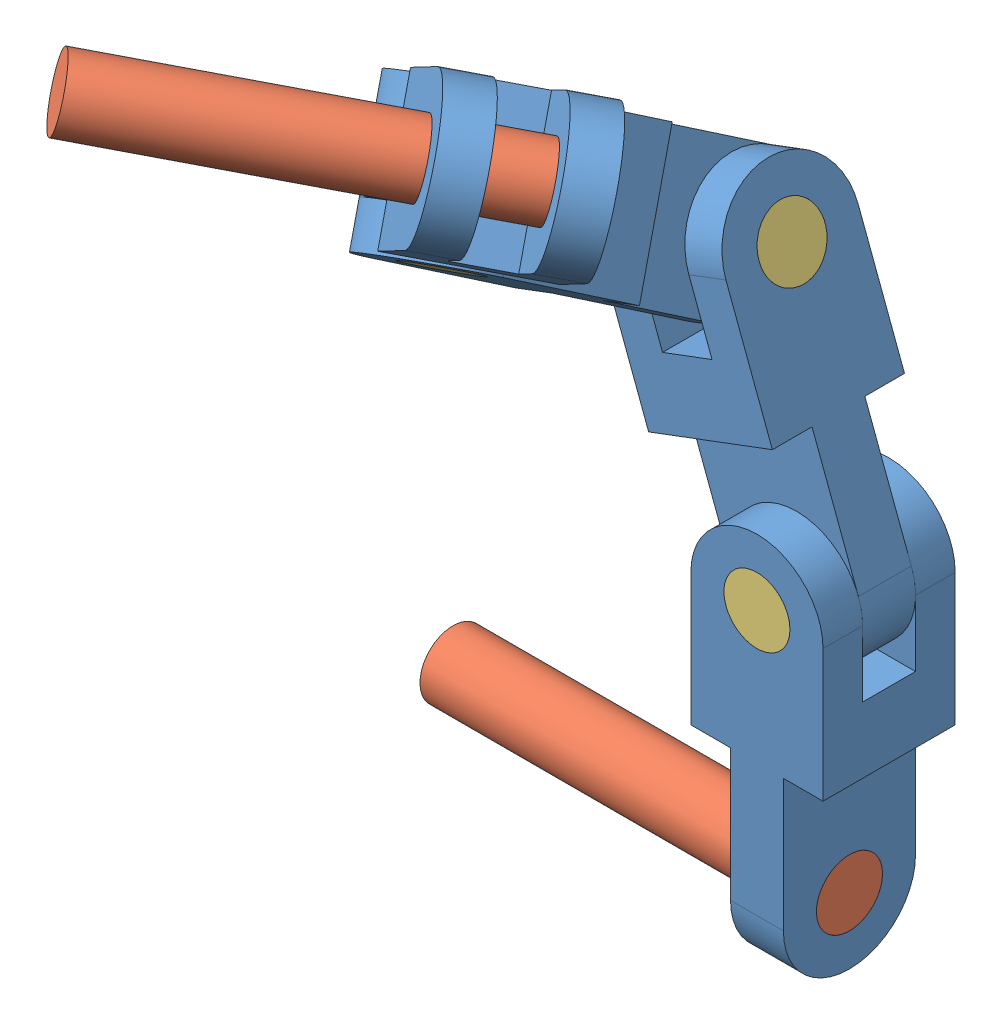
SolidWorks assembly Assem1 - Screens, configuration Default. Lengths in mm.
Overall size (388.38 745.02 528.55).
9 component instances, 3 part files, 19 mates.
Components (placement in the parent):
- chain_link-1: chain_link [Default] at (62.1432 144.0475 265.0733) size (100 300 100)
- long_pin-1: long_pin [Default] at (-217.8568 44.0475 265.0733) x (0 -0.416693 0.909047) z (0 -0.909047 -0.416693) size (50 300 50)
- short_pin-1: short_pin [Default] at (62.1432 244.0475 215.0733) x (1 0 0) z (0 1 0) size (50 100 50)
- chain_link-2: chain_link [Default] at (27.0048 337.6706 265.0733) x (0 0 1) z (-0.936232 -0.351384 0) size (100 300 100)
- chain_link-4: chain_link [Default] at (-27.2234 482.1572 349.0285) x (0.936232 0.351384 0) z (0.295005 -0.786016 0.543278) size (100 300 100)
- short_pin-3: short_pin [Default] at (-54.9451 413.7246 265.0733) x (-0.351384 0.936232 0) z (0 0 1) size (50 100 50)
- chain_link-5: chain_link [Default] at (20.9473 590.4881 479.6046) x (-0.295005 0.786016 -0.543278) z (0.678655 -0.227879 -0.698211) size (100 300 100)
- short_pin-4: short_pin [Default] at (-31.5631 493.7199 460.1477) x (0.703647 0.563374 0.433003) z (0.646416 -0.254538 -0.719275) size (50 100 50)
- long_pin-2: long_pin [Default] at (-81.4557 704.9252 700.7782) x (0.564085 0.77053 0.296803) z (0.470357 -0.595277 0.651467) size (50 300 50)
Mates (geometry in assembly coordinates):
- Concentric1: concentric anti-aligned: cylinder of chain_link-1 through (12.1432 44.0475 265.0733) axis (1 0 0) radius 25; axis of long_pin-1 through (82.1432 44.0475 265.0733) axis (-1 0 0)
- Coincident1: coincident anti-aligned: circle of chain_link-1; circle of long_pin-1
- Concentric2: concentric anti-aligned: cylinder of short_pin-1 through (62.1432 244.0475 315.0733) axis (0 0 -1) radius 25; cylinder of chain_link-2 through (62.1432 244.0475 215.0733) axis (0 0 1) radius 25
- Concentric3: concentric anti-aligned: cylinder of chain_link-1 through (62.1432 244.0475 215.0733) axis (0 0 1) radius 25; cylinder of short_pin-1 through (62.1432 244.0475 315.0733) axis (0 0 -1) radius 25
- Coincident2: coincident aligned: plane of chain_link-1 through (62.1432 244.0475 215.0733) normal (0 0 -1); circle of short_pin-1
- Coincident3: coincident anti-aligned: plane of chain_link-1 through (12.1432 294.0475 285.0733) normal (0 0 -1); plane of chain_link-2 through (62.1432 244.0475 285.0733) normal (0 0 1)
- Concentric8: concentric anti-aligned: line of chain_link-4 through (-26.8582 424.2661 265.0733) axis (0.936232 0.351384 0); cylinder of short_pin-3 through (38.678 448.863 265.0733) axis (-0.936232 -0.351384 0) radius 25
- Concentric9: concentric aligned: cylinder of chain_link-2 through (38.678 448.863 265.0733) axis (-0.936232 -0.351384 0) radius 25; cylinder of short_pin-3 through (38.678 448.863 265.0733) axis (-0.936232 -0.351384 0) radius 25
- Concentric10: concentric aligned: cylinder of chain_link-2 through (38.678 448.863 265.0733) axis (-0.936232 -0.351384 0) radius 25; cylinder of short_pin-3 through (38.678 448.863 265.0733) axis (-0.936232 -0.351384 0) radius 25
- Coincident9: coincident anti-aligned: plane of chain_link-2 through (38.678 448.863 265.0733) normal (0.936232 0.351384 0); circle of short_pin-3
- Coincident10: coincident anti-aligned: plane of chain_link-2 through (-6.9781 485.1331 215.0733) normal (-0.936232 -0.351384 0); plane of chain_link-4 through (10.5911 438.3215 265.0733) normal (0.936232 0.351384 0)
- Concentric11: concentric anti-aligned: cylinder of chain_link-5 through (-31.5631 493.7199 460.1477) axis (-0.295005 0.786016 -0.543278) radius 25; cylinder of short_pin-4 through (-61.0636 572.3214 405.8199) axis (0.295005 -0.786016 0.543278) radius 25
- Concentric12: concentric aligned: cylinder of chain_link-4 through (-61.0636 572.3214 405.8199) axis (0.295005 -0.786016 0.543278) radius 25; cylinder of short_pin-4 through (-61.0636 572.3214 405.8199) axis (0.295005 -0.786016 0.543278) radius 25
- Concentric13: concentric aligned: cylinder of chain_link-4 through (-61.0636 572.3214 405.8199) axis (0.295005 -0.786016 0.543278) radius 25; cylinder of short_pin-4 through (-61.0636 572.3214 405.8199) axis (0.295005 -0.786016 0.543278) radius 25
- Concentric14: concentric aligned: cylinder of chain_link-4 through (-61.0636 572.3214 405.8199) axis (0.295005 -0.786016 0.543278) radius 25; cylinder of short_pin-4 through (-61.0636 572.3214 405.8199) axis (0.295005 -0.786016 0.543278) radius 25
- Coincident11: coincident anti-aligned: plane of chain_link-4 through (-108.57 556.6035 464.0959) normal (0.295005 -0.786016 0.543278); plane of chain_link-5 through (-52.2135 548.741 422.1183) normal (-0.295005 0.786016 -0.543278)
- Coincident12: coincident aligned: plane of chain_link-4 through (-31.5631 493.7199 460.1477) normal (0.295005 -0.786016 0.543278); circle of short_pin-4
- Concentric15: concentric anti-aligned: cylinder of chain_link-5 through (54.2753 659.3494 561.1359) axis (0.678655 -0.227879 -0.698211) radius 25; cylinder of long_pin-2 through (122.1407 636.5616 491.3148) axis (-0.678655 0.227879 0.698211) radius 25
- Coincident13: coincident anti-aligned: plane of chain_link-5 through (122.1407 636.5616 491.3148) normal (0.678655 -0.227879 -0.698211); circle of long_pin-2
